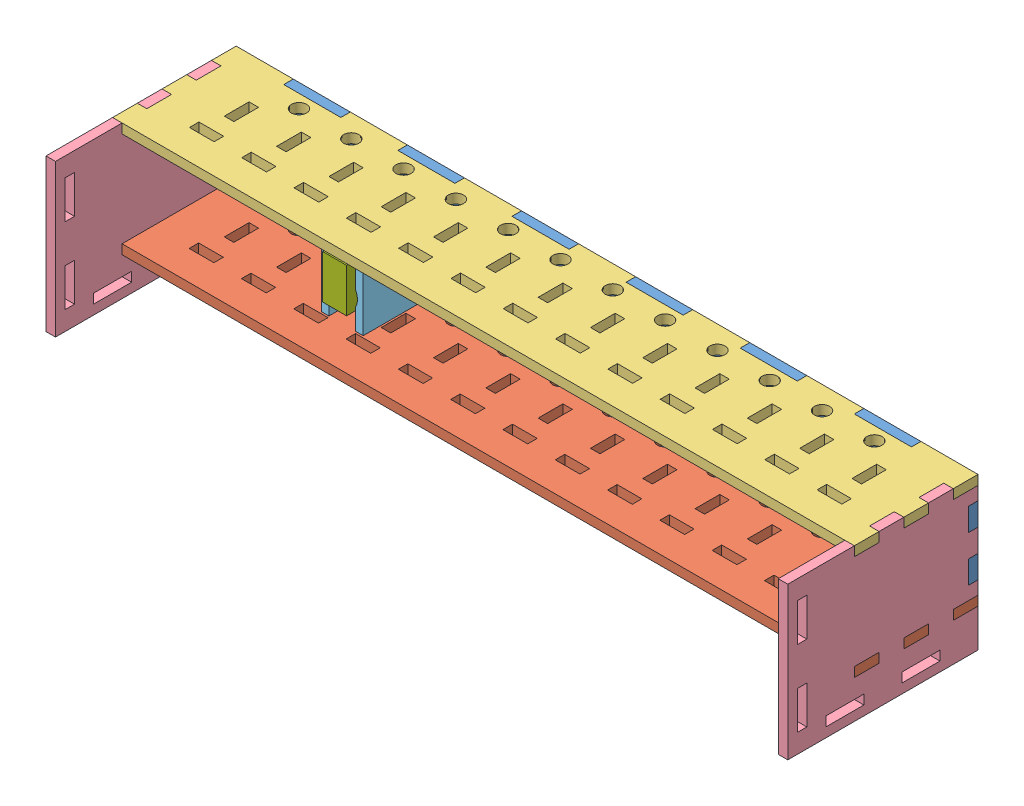
SolidWorks assembly A_SupportDistributeur, configuration Défaut. Lengths in mm.
Overall size (390 80 100).
9 component instances, 7 part files, 47 mates.
Components (placement in the parent):
- BaseSupport-1: BaseSupport [Défaut] at (-173.4428 -0.6213 387.5) size (390 60 5)
- FrontSupport-1: FrontSupport [Défaut] at (-173.4428 -55.6213 452.5) x (1 0 0) z (0 -1 0) size (390 65 5)
- BackSupport-1: BackSupport [Défaut] at (-173.4428 -0.6213 452.5) x (1 0 0) z (0 -1 0) size (390 65 5)
- LeftSupport-1: LeftSupport [Défaut] at (-168.4428 -0.6213 452.5) x (-1 0 0) z (0 1 0) size (5 100 80)
- LeftSupport-2: LeftSupport [Défaut] at (216.5572 -0.6213 452.5) x (-1 0 0) z (0 1 0) size (5 100 80)
- A_Distributeur_2-1: A_Distributeur_2 [Défaut] at (-74.8549 -30.5009 367) x (0 1 0) z (0 0 1) size (49.5 22 43)
  - socle-1: socle [Défaut] at (-24.6204 9.8379 35.5) size (49.5 22 39)
  - Vis-1: Vis [Défaut] at (-9.6204 -1.1621 31.5) x (-0.159197 -0.987247 0) z (-0.987247 0.159197 0) size (13.7 10.52 14.01)
  - servo-1: servo [Predeterminado] at (-4.4204 -7.4621 68.5) x (1 0 0) z (0 1 0) size (32.6 27 12.6)
Mates (geometry in assembly coordinates):
- Coïncidente31: coincident aligned: plane of BaseSupport-1 through (-173.4428 -60.6213 392.5) normal (0 -1 0); plane of FrontSupport-1 through (-173.4428 -60.6213 452.5) normal (0 -1 0)
- Coïncidente32: coincident aligned: plane of BaseSupport-1 through (-173.4428 -0.6213 387.5) normal (0 0 -1); plane of FrontSupport-1 through (-173.4428 -60.6213 387.5) normal (0 0 -1)
- Coïncidente33: coincident aligned: plane of BaseSupport-1 through (-173.4428 -0.6213 392.5) normal (-1 0 0); plane of FrontSupport-1 through (-173.4428 -60.6213 452.5) normal (-1 0 0)
- Coïncidente34: coincident anti-aligned: plane of BaseSupport-1 through (-113.4428 -5.6213 387.5) normal (0 1 0); plane of BackSupport-1 through (-173.4428 -5.6213 452.5) normal (0 -1 0)
- Coïncidente35: coincident aligned: plane of BaseSupport-1 through (-173.4428 -0.6213 392.5) normal (-1 0 0); plane of BackSupport-1 through (-173.4428 -5.6213 452.5) normal (-1 0 0)
- Coïncidente36: coincident aligned: plane of BaseSupport-1 through (-173.4428 -0.6213 387.5) normal (0 0 -1); plane of BackSupport-1 through (-173.4428 -5.6213 387.5) normal (0 0 -1)
- Coïncidente37: coincident aligned: plane of FrontSupport-1 through (-173.4428 -60.6213 452.5) normal (0 -1 0); plane of ? through (-140.9428 -60.6213 414.5) normal (0 -1 0)
- Coïncidente38: coincident anti-aligned: plane of BackSupport-1 through (-153.9428 -0.6213 419.5) normal (0 0 -1); plane of ? through (-140.9428 -60.6213 419.5) normal (0 0 1)
- Coïncidente39: coincident anti-aligned: plane of BackSupport-1 through (-153.9428 -0.6213 419.5) normal (1 0 0); plane of ? through (-153.9428 -60.6213 414.5) normal (-1 0 0)
- Coïncidente40: coincident aligned: plane of FrontSupport-1 through (-173.4428 -60.6213 452.5) normal (0 -1 0); plane of ? through (-103.4428 -60.6213 414.5) normal (0 -1 0)
- Coïncidente41: coincident aligned: plane of FrontSupport-1 through (-173.4428 -60.6213 452.5) normal (0 -1 0); plane of ? through (-65.9428 -60.6213 414.5) normal (0 -1 0)
- Coïncidente42: coincident aligned: plane of FrontSupport-1 through (-173.4428 -60.6213 452.5) normal (0 -1 0); plane of ? through (-28.4428 -60.6213 414.5) normal (0 -1 0)
- Coïncidente43: coincident aligned: plane of FrontSupport-1 through (-173.4428 -60.6213 452.5) normal (0 -1 0); plane of ? through (9.0572 -60.6213 414.5) normal (0 -1 0)
- Coïncidente44: coincident aligned: plane of FrontSupport-1 through (-173.4428 -60.6213 452.5) normal (0 -1 0); plane of ? through (46.5572 -60.6213 414.5) normal (0 -1 0)
- Coïncidente45: coincident aligned: plane of FrontSupport-1 through (-173.4428 -60.6213 452.5) normal (0 -1 0); plane of ? through (84.0572 -60.6213 414.5) normal (0 -1 0)
- Coïncidente46: coincident aligned: plane of FrontSupport-1 through (-173.4428 -60.6213 452.5) normal (0 -1 0); plane of ? through (121.5572 -60.6213 414.5) normal (0 -1 0)
- Coïncidente47: coincident aligned: plane of FrontSupport-1 through (-173.4428 -60.6213 452.5) normal (0 -1 0); plane of ? through (159.0572 -60.6213 414.5) normal (0 -1 0)
- Coïncidente48: coincident aligned: plane of FrontSupport-1 through (-173.4428 -60.6213 452.5) normal (0 -1 0); plane of ? through (196.5572 -60.6213 414.5) normal (0 -1 0)
- Coïncidente49: coincident anti-aligned: plane of FrontSupport-1 through (-116.4428 -55.6213 419.5) normal (1 0 0); plane of ? through (-116.4428 -60.6213 414.5) normal (-1 0 0)
- Coïncidente50: coincident anti-aligned: plane of FrontSupport-1 through (-116.4428 -55.6213 414.5) normal (0 0 1); plane of ? through (-103.4428 -60.6213 414.5) normal (0 0 -1)
- Coïncidente51: coincident anti-aligned: plane of FrontSupport-1 through (-78.9428 -55.6213 419.5) normal (0 0 -1); plane of ? through (-65.9428 -60.6213 419.5) normal (0 0 1)
- Coïncidente52: coincident anti-aligned: plane of FrontSupport-1 through (-78.9428 -55.6213 419.5) normal (1 0 0); plane of ? through (-78.9428 -60.6213 414.5) normal (-1 0 0)
- Coïncidente53: coincident anti-aligned: plane of FrontSupport-1 through (-41.4428 -55.6213 419.5) normal (0 0 -1); plane of ? through (-28.4428 -60.6213 419.5) normal (0 0 1)
- Coïncidente54: coincident anti-aligned: plane of FrontSupport-1 through (-28.4428 -55.6213 419.5) normal (-1 0 0); plane of ? through (-28.4428 -60.6213 414.5) normal (1 0 0)
- Coïncidente55: coincident anti-aligned: plane of FrontSupport-1 through (-3.9428 -55.6213 419.5) normal (0 0 -1); plane of ? through (9.0572 -60.6213 419.5) normal (0 0 1)
- Coïncidente56: coincident anti-aligned: plane of FrontSupport-1 through (9.0572 -55.6213 419.5) normal (-1 0 0); plane of ? through (9.0572 -60.6213 414.5) normal (1 0 0)
- Coïncidente57: coincident: line of FrontSupport-1 through (46.5572 -55.6213 419.5) axis (-1 0 0); plane of ? through (46.5572 -60.6213 419.5) normal (0 0 1)
- Coïncidente58: coincident anti-aligned: plane of FrontSupport-1 through (46.5572 -55.6213 419.5) normal (-1 0 0); plane of ? through (46.5572 -60.6213 414.5) normal (1 0 0)
- Coïncidente59: coincident anti-aligned: plane of FrontSupport-1 through (71.0572 -55.6213 419.5) normal (0 0 -1); plane of ? through (84.0572 -60.6213 419.5) normal (0 0 1)
- Coïncidente60: coincident anti-aligned: plane of FrontSupport-1 through (84.0572 -55.6213 419.5) normal (-1 0 0); plane of ? through (84.0572 -60.6213 414.5) normal (1 0 0)
- Coïncidente61: coincident anti-aligned: plane of FrontSupport-1 through (108.5572 -55.6213 419.5) normal (0 0 -1); plane of ? through (121.5572 -60.6213 419.5) normal (0 0 1)
- Coïncidente62: coincident anti-aligned: plane of FrontSupport-1 through (121.5572 -55.6213 419.5) normal (-1 0 0); plane of ? through (121.5572 -60.6213 414.5) normal (1 0 0)
- Coïncidente63: coincident anti-aligned: plane of FrontSupport-1 through (146.0572 -55.6213 419.5) normal (0 0 -1); plane of ? through (159.0572 -60.6213 419.5) normal (0 0 1)
- Coïncidente64: coincident anti-aligned: plane of FrontSupport-1 through (159.0572 -55.6213 419.5) normal (-1 0 0); plane of ? through (159.0572 -60.6213 414.5) normal (1 0 0)
- Coïncidente65: coincident anti-aligned: plane of FrontSupport-1 through (183.5572 -55.6213 419.5) normal (0 0 -1); plane of ? through (196.5572 -60.6213 419.5) normal (0 0 1)
- Coïncidente66: coincident anti-aligned: plane of FrontSupport-1 through (196.5572 -55.6213 419.5) normal (-1 0 0); plane of ? through (196.5572 -60.6213 414.5) normal (1 0 0)
- Coïncidente67: coincident aligned: plane of BaseSupport-1 through (-173.4428 -0.6213 387.5) normal (0 0 -1); plane of LeftSupport-1 through (-173.4428 -0.6213 387.5) normal (0 0 -1)
- Coïncidente68: coincident aligned: plane of BackSupport-1 through (-173.4428 -0.6213 452.5) normal (0 1 0); plane of LeftSupport-1 through (-173.4428 -0.6213 452.5) normal (0 1 0)
- Coïncidente69: coincident aligned: plane of BaseSupport-1 through (-173.4428 -0.6213 392.5) normal (-1 0 0); plane of LeftSupport-1 through (-173.4428 -0.6213 452.5) normal (-1 0 0)
- Coïncidente71: coincident aligned: plane of BaseSupport-1 through (-173.4428 -0.6213 387.5) normal (0 0 -1); plane of LeftSupport-2 through (211.5572 -0.6213 387.5) normal (0 0 -1)
- Coïncidente72: coincident aligned: plane of BackSupport-1 through (216.5572 -5.6213 452.5) normal (1 0 0); plane of LeftSupport-2 through (216.5572 -0.6213 452.5) normal (1 0 0)
- Coïncidente73: coincident aligned: plane of FrontSupport-1 through (-173.4428 -60.6213 452.5) normal (0 -1 0); plane of ? through (-65.9428 -60.6213 445.5) normal (0 -1 0)
- Coïncidente74: coincident anti-aligned: plane of BackSupport-1 through (-78.9428 -0.6213 445.5) normal (0 0 1); plane of ? through (-65.9428 -60.6213 445.5) normal (0 0 -1)
- Coïncidente75: coincident anti-aligned: plane of BackSupport-1 through (-65.9428 -0.6213 450.5) normal (-1 0 0); plane of ? through (-65.9428 -60.6213 445.5) normal (1 0 0)
- Coïncidente76: coincident anti-aligned: plane of BackSupport-1 through (-173.4428 -5.6213 452.5) normal (0 -1 0); plane of A_Distributeur_2-1/socle-1 through (-84.6928 -5.6213 402.5) normal (0 1 0)
- Coïncidente77: coincident anti-aligned: plane of BaseSupport-1 through (-173.4428 -0.6213 392.5) normal (0 0 1); plane of A_Distributeur_2-1/socle-1 through (-84.6928 -55.1213 392.5) normal (0 0 -1)
- Coïncidente78: coincident aligned: plane of FrontSupport-1 through (-84.6928 -55.6213 422.5) normal (-1 0 0); plane of A_Distributeur_2-1/socle-1 through (-84.6928 -55.1213 406.5) normal (-1 0 0)
